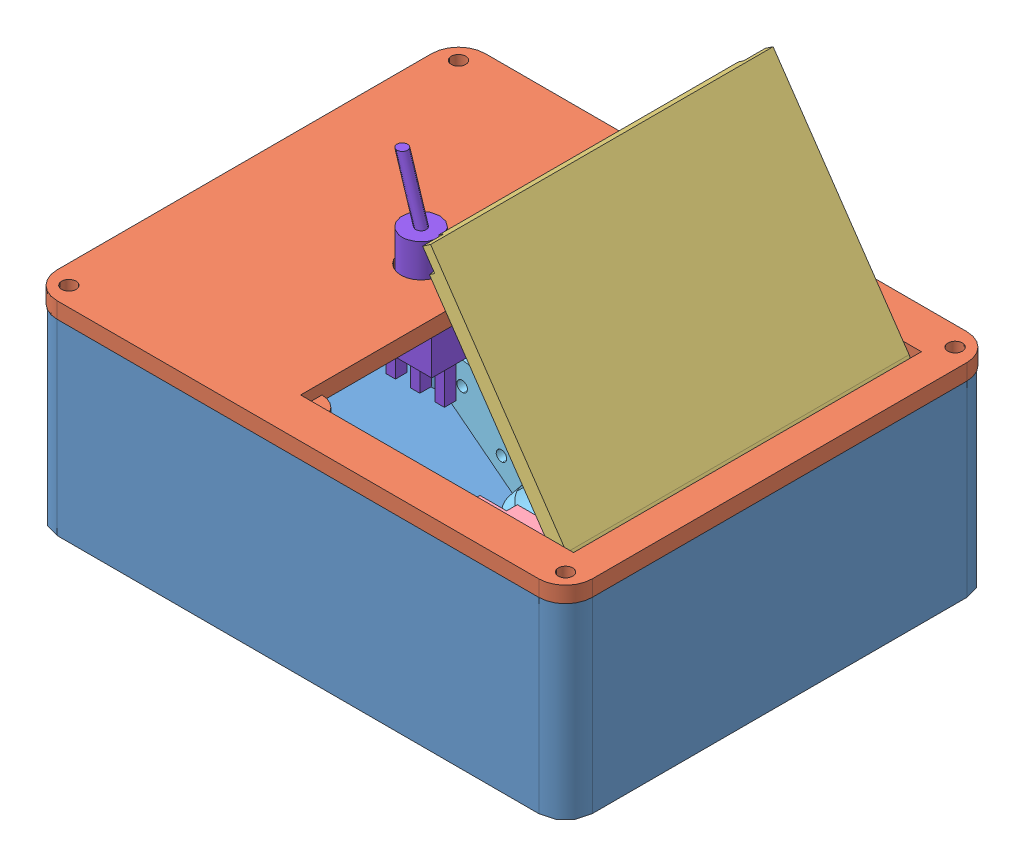
SolidWorks assembly Assemb1, configuration Default. Lengths in mm.
Overall size (103.6 79.09 80).
9 component instances, 8 part files, 21 mates.
Components (placement in the parent):
- Bottom-1: Bottom [Default] at (24.7146 34.1005 82.1131) size (100 35 80)
- Cover-1: Cover [Default] at (24.7146 69.1005 82.1131) size (100 7 80)
- Lip-1: Lip [Default] at (53.3617 86.6896 82.6131) x (0.564805 -0.825224 0) z (0 0 1) size (49 7 64)
- Servo-1: Servo [Default] at (7.2146 47.1005 58.1131) size (33 12 27)
- Arm-7: Arm [Default] at (30.6042 52.6025 83.6131) x (-0.621276 0.783591 0) z (-0.783591 -0.621276 0) size (30.99 9.28 38.88)
- Servo-4: Servo [Default] at (54.2146 59.1005 111.1131) x (1 0 0) z (0 0 -1) size (33 12 27)
- Stick-1: Stick [Default] at (54.4975 69.481 92.1131) x (0.281462 -0.959572 0) z (-0.959572 -0.281462 0) size (44.4 4 8)
- DC005-1: DC005 [Default] at (-28.8854 50.5194 82.1131) x (0 0 -1) z (1 0 0) size (9.8 15 14)
- Swtich-1: Swtich [Default] at (7.7146 59.1005 82.1131) size (13 37.1 9)
Mates (geometry in assembly coordinates):
- 同心1: concentric anti-aligned: cylinder of Bottom-1 through (-21.6854 65.1005 45.7131) axis (0 1 0) radius 1.35; cylinder of Cover-1 through (-21.6854 72.1005 45.7131) axis (0 -1 0) radius 1.35
- 同心2: concentric anti-aligned: cylinder of Bottom-1 through (71.1146 65.1005 45.7131) axis (0 1 0) radius 1.35; cylinder of Cover-1 through (71.1146 72.1005 45.7131) axis (0 -1 0) radius 1.35
- 重合1: coincident anti-aligned: plane of Bottom-1 through (-20.2854 69.1005 117.1131) normal (0 1 0); plane of Cover-1 through (-20.2854 69.1005 117.1131) normal (0 -1 0)
- 同心3: concentric anti-aligned: cylinder of lip-1 through (64.7146 67.8005 114.6131) axis (0 0 -1) radius 1.15; cylinder of Cover-1 through (64.7146 67.8005 45.6131) axis (0 0 1) radius 1.15
- 重合4: coincident aligned: plane of Bottom-1 through (24.7146 59.1005 82.1131) normal (0 1 0); plane of servo-1 through (7.2146 59.1005 58.1131) normal (0 1 0)
- 重合10: coincident anti-aligned: plane of Cover-1 through (17.7146 72.1005 114.6131) normal (0 0 -1); plane of lip-1 through (41.9996 108.602 114.6131) normal (0 0 1)
- 同心11: concentric anti-aligned: cylinder of arm-7 through (12.4064 53.1005 74.6131) axis (0 0 1) radius 1; cylinder of servo-1 through (12.4064 53.1005 77.1131) axis (0 0 -1) radius 1.3
- 重合24: coincident anti-aligned: plane of servo-1 through (12.4064 53.1005 77.1131) normal (0 0 1); plane of arm-7 through (30.6042 52.6025 77.1131) normal (0 0 -1)
- 重合27: coincident anti-aligned: plane of Bottom-1 through (24.7146 59.1005 103.1131) normal (0 0 -1); plane of servo-4 through (54.2146 59.1005 103.1131) normal (0 0 1)
- 重合28: coincident anti-aligned: plane of Bottom-1 through (24.7146 59.1005 66.1131) normal (0 0 1); plane of servo-1 through (7.2146 47.1005 66.1131) normal (0 0 -1)
- 重合29: coincident anti-aligned: plane of Bottom-1 through (19.2146 47.1005 66.1131) normal (-1 0 0); plane of servo-1 through (19.2146 59.1005 50.1131) normal (1 0 0)
- 重合32: coincident anti-aligned: plane of Bottom-1 through (66.2146 47.1005 103.1131) normal (-1 0 0); plane of servo-4 through (66.2146 47.1005 119.1131) normal (1 0 0)
- 重合33: coincident anti-aligned: plane of Bottom-1 through (24.7146 47.1005 82.1131) normal (0 1 0); plane of servo-4 through (54.2146 47.1005 111.1131) normal (0 -1 0)
- 同心12: concentric aligned: cylinder of servo-4 through (59.4064 53.1005 92.1131) axis (0 0 1) radius 1.3; cylinder of stick-1 through (59.4064 53.1005 92.6131) axis (0 0 1) radius 1.1
- 重合34: coincident aligned: plane of servo-4 through (59.4064 53.1005 92.1131) normal (0 0 -1); plane of stick-1 through (59.4064 53.1005 92.1131) normal (0 0 -1)
- Coincident1: coincident anti-aligned: plane of Bottom-1 through (-25.2854 69.1005 47.1131) normal (-1 0 0); plane of DC005-1 through (-25.2854 45.5194 86.1131) normal (1 0 0)
- Concentric1: concentric aligned: cylinder of Bottom-1 through (-22.2854 51.5194 82.1131) axis (-1 0 0) radius 5; cylinder of DC005-1 through (-14.8854 51.5194 82.1131) axis (-1 0 0) radius 3.2
- Tangent1: tangent anti-aligned: plane of lip-1 through (53.3617 86.6896 82.6131) normal (-0.825224 -0.564805 0); cylinder of stick-1 through (48.6283 90.0645 96.1131) axis (0 0 -1) radius 2
- Concentric3: concentric anti-aligned: cylinder of Cover-1 through (7.7146 69.1005 82.1131) axis (0 1 0) radius 3.75; cylinder of Swtich-1 through (7.7146 78.1005 82.1131) axis (0 -1 0) radius 3.5
- Coincident2: coincident anti-aligned: plane of Cover-1 through (-20.2854 69.1005 117.1131) normal (0 -1 0); plane of Swtich-1 through (7.7146 69.1005 82.1131) normal (0 1 0)
- Parallel1: parallel anti-aligned: plane of Bottom-1 through (-22.2854 69.1005 47.1131) normal (1 0 0); plane of Swtich-1 through (1.2146 69.1005 77.6131) normal (-1 0 0)
